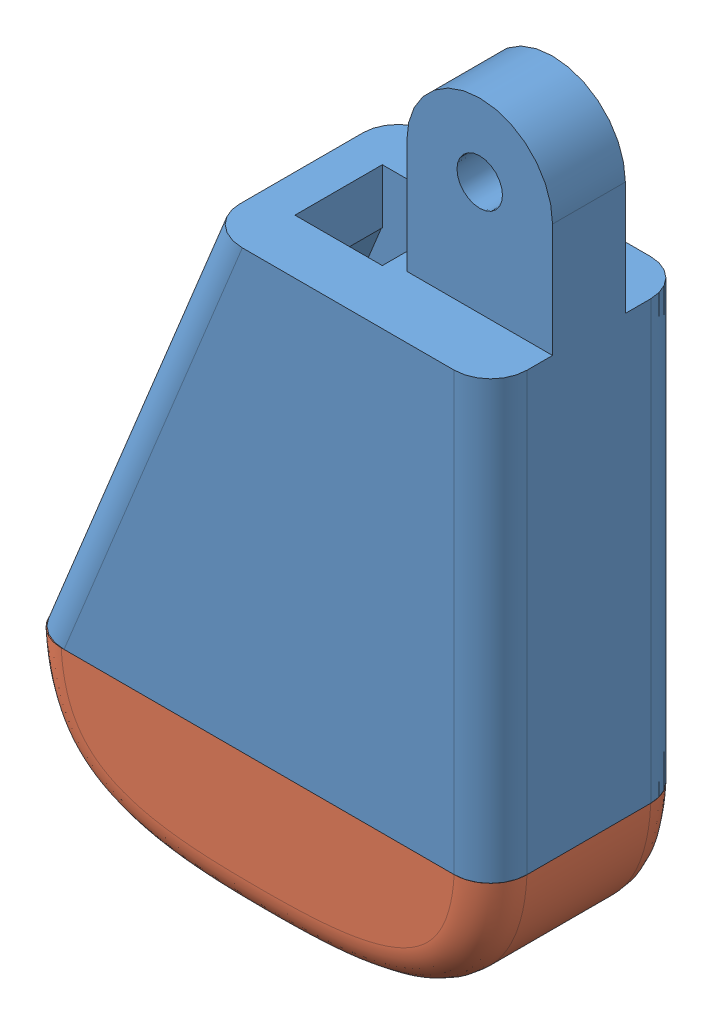
SolidWorks assembly Assem1, configuration Default. Lengths in mm.
Overall size (28.22 43.56 11.03).
2 component instances, 2 part files, 2 mates.
Components (placement in the parent):
- GLaDOS blinder-1: GLaDOS blinder [Default] at (-6.2925 -26.1947 9.0349) size (25.59 35.25 10.8)
- GLaDOS faceplate-1: GLaDOS faceplate [Default] at (-6.0895 -25.1947 9.0349) x (1 0 0) z (0 0 -1) size (28.22 10.63 11.03)
Mates (geometry in assembly coordinates):
- Coincident1: coincident anti-aligned: line of GLaDOS blinder-1 through (-16.7244 -25.1947 14.4349) axis (1 0 0); line of GLaDOS faceplate-1 through (4.7027 -25.1947 14.4349) axis (-1 0 0)
- Coincident3: coincident anti-aligned: line of GLaDOS blinder-1 through (-18.8845 -25.1947 5.6349) axis (0 0 1); line of GLaDOS faceplate-1 through (-18.8845 -25.1947 12.4349) axis (0 0 -1)
